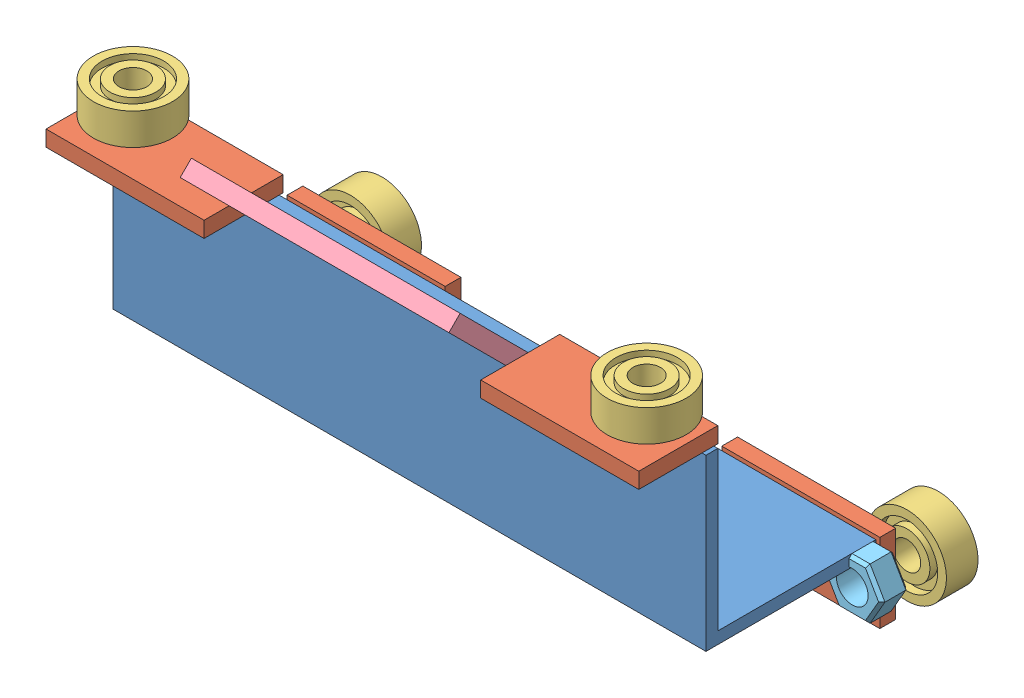
SolidWorks assembly СбКаретка, configuration По умолчанию. Lengths in mm.
Overall size (160.84 88.25 88.25).
12 component instances, 5 part files, 28 mates.
Components (placement in the parent):
- Угольник40_150-1: Угольник40_150 [По умолчанию] at origin size (150 43 43)
- Пластина20_4_150-1: Пластина20_4_150 [По умолчанию] at (150 41 20) x (-1 0 0) z (0 -1 0) size (40 20 4)
- Пластина20_4_150-3: Пластина20_4_150 [По умолчанию] at (0 45 20) x (1 0 0) z (0 1 0) size (40 20 4)
- Подшипник20_8_7-1: Подшипник20_8_7 [По умолчанию] at (10 47 8) x (1 0 0) z (0 -1 0) size (20 20 8)
- Подшипник20_8_7-2: Подшипник20_8_7 [По умолчанию] at (140 47 8) x (1 0 0) z (0 -1 0) size (20 20 8)
- Пластина20_4_150-4: Пластина20_4_150 [По умолчанию] at (0 -20 -41) size (40 20 4)
- Пластина20_4_150-5: Пластина20_4_150 [По умолчанию] at (150 -20 -45) x (-1 0 0) z (0 0 -1) size (40 20 4)
- Подшипник20_8_7-3: Подшипник20_8_7 [По умолчанию] at (150.8421 -6.5 -47) x (-1 0 0) z (0 0 1) size (20 20 8)
- Подшипник20_8_7-4: Подшипник20_8_7 [По умолчанию] at (10 -8 -47) x (-1 0 0) z (0 0 1) size (20 20 8)
- Пластина45-1: Пластина45 [По умолчанию] at (41 58.3848 27.0416) x (1 0 0) z (0 0.707107 0.707107) size (68 4 30)
- Пластина45-2: Пластина45 [По умолчанию] at (41 -24.2132 -61.2132) x (1 0 0) z (0 -0.707107 -0.707107) size (68 4 30)
- ГайкаМ8-1: ГайкаМ8 [По умолчанию] at (150.8421 -6.5 -40) size (15.01 13 6.8)
Mates (geometry in assembly coordinates):
- Совпадение2: coincident aligned: plane of Угольник45_150-1 through (150 0 0) normal (1 0 0); plane of Пластина20_4_150-1 through (150 41 20) normal (1 0 0)
- Совпадение3: coincident aligned: plane of Угольник45_150-1 through (150 40 0) normal (0 0 -1); plane of Пластина20_4_150-1 through (110 41 0) normal (0 0 -1)
- Расстояние1: distance = 1 mm anti-aligned: plane of Пластина20_4_150-1 through (110 41 20) normal (0 -1 0); plane of Угольник45_150-1 through (150 40 3) normal (0 1 0)
- Совпадение5: coincident aligned: plane of Угольник45_150-1 through (0 0 0) normal (-1 0 0); plane of Пластина20_4_150-3 through (0 45 20) normal (-1 0 0)
- Концентричный2: concentric anti-aligned: cylinder of Пластина20_4_150-1 through (140 41 8) axis (0 1 0) radius 3.1; cylinder of Подшипник20_8_7-2 through (140 23.6857 8) axis (0 -1 0) radius 3.5
- Совпадение9: coincident aligned: plane of Подшипник20_8_7-1 through (10 55 13.8254) normal (0 1 0); plane of Подшипник20_8_7-2 through (140 55 13.8254) normal (0 1 0)
- Совпадение11: coincident aligned: plane of Пластина20_4_150-1 through (110 41 0) normal (0 0 -1); plane of Пластина20_4_150-3 through (40 45 0) normal (0 0 -1)
- Совпадение12: coincident aligned: plane of Пластина20_4_150-1 through (110 45 20) normal (0 1 0); plane of Пластина20_4_150-3 through (40 45 20) normal (0 1 0)
- Концентричный3: concentric aligned: cylinder of Пластина20_4_150-3 through (10 45 8) axis (0 -1 0) radius 3.1; cylinder of Подшипник20_8_7-1 through (10 23.6857 8) axis (0 -1 0) radius 3.5
- Концентричный4: concentric anti-aligned: cylinder of Пластина20_4_150-4 through (10 -8 -41) axis (0 0 -1) radius 3.1; cylinder of Подшипник20_8_7-4 through (10 -8 -23.6857) axis (0 0 1) radius 3.5
- Совпадение13: coincident aligned: plane of Подшипник20_8_7-3 through (154.5948 0.6746 -55) normal (0 0 -1); plane of Подшипник20_8_7-4 through (10 -13.8254 -55) normal (0 0 -1)
- Совпадение14: coincident aligned: plane of Пластина20_4_150-4 through (40 -20 -45) normal (0 0 -1); plane of Пластина20_4_150-5 through (110 -20 -45) normal (0 0 -1)
- Совпадение15: coincident aligned: plane of Пластина20_4_150-4 through (40 0 -41) normal (0 1 0); plane of Пластина20_4_150-5 through (110 0 -45) normal (0 1 0)
- Совпадение16: coincident aligned: plane of Угольник45_150-1 through (150 0 0) normal (0 1 0); plane of Пластина20_4_150-4 through (40 0 -41) normal (0 1 0)
- Совпадение18: coincident aligned: plane of Угольник45_150-1 through (0 0 0) normal (-1 0 0); plane of Пластина20_4_150-4 through (0 -20 -41) normal (-1 0 0)
- Расстояние2: distance = 1 mm anti-aligned: plane of Пластина20_4_150-4 through (40 -20 -41) normal (0 0 1); plane of Угольник45_150-1 through (150 0 -40) normal (0 0 -1)
- Расстояние3: distance = 2 mm anti-aligned: plane of Подшипник20_8_7-4 through (10 -11.5 -47) normal (0 0 1); plane of Пластина20_4_150-4 through (40 -20 -45) normal (0 0 -1)
- Совпадение21: coincident aligned: plane of Угольник45_150-1 through (150 0 0) normal (1 0 0); plane of Пластина20_4_150-5 through (150 -20 -45) normal (1 0 0)
- Расстояние4: distance = 2 mm anti-aligned: plane of Подшипник20_8_7-2 through (140 47 11.5) normal (0 -1 0); plane of Пластина20_4_150-1 through (110 45 20) normal (0 1 0)
- Совпадение23: coincident aligned: line of Угольник40_150-1 through (150 40 3) axis (-1 0 0); line of Пластина45-1 through (109 40 3) axis (-1 0 0)
- Угол1: planar angle = 2.356194 rad aligned: plane of Пластина45-1 through (41 61.2132 24.2132) normal (0 0.707107 -0.707107); plane of Угольник40_150-1 through (150 40 3) normal (0 0 1)
- Совпадение28: coincident aligned: line of Угольник40_150-1 through (150 -3 -40) axis (-1 0 0); line of Пластина45-2 through (109 -3 -40) axis (-1 0 0)
- Параллельность3: parallel aligned: plane of Пластина45-1 through (41 58.3848 27.0416) normal (0 -0.707107 0.707107); plane of Пластина45-2 through (41 -27.0416 -58.3848) normal (0 -0.707107 0.707107)
- Расстояние5: distance = 1 mm anti-aligned: plane of Пластина20_4_150-1 through (110 41 20) normal (-1 0 0); plane of Пластина45-1 through (109 61.2132 24.2132) normal (1 0 0)
- Совпадение32: coincident aligned: plane of Пластина45-1 through (109 61.2132 24.2132) normal (1 0 0); plane of Пластина45-2 through (109 -27.0416 -58.3848) normal (1 0 0)
- Совпадение33: coincident aligned: plane of Угольник40_150-1 through (150 0 0) normal (0 1 0); plane of ГайкаМ8-1 through (154.5948 0 -33.2) normal (0 1 0)
- Совпадение34: coincident aligned: plane of Угольник40_150-1 through (150 0 -40) normal (0 0 -1); plane of ГайкаМ8-1 through (154.5948 6.5 -40) normal (0 0 -1)
- Концентричный7: concentric anti-aligned: cylinder of Подшипник20_8_7-3 through (154.5948 6.5 -23.6857) axis (0 0 1) radius 3.5; cylinder of ГайкаМ8-1 through (154.5948 6.5 -33.2) axis (0 0 -1) radius 4
